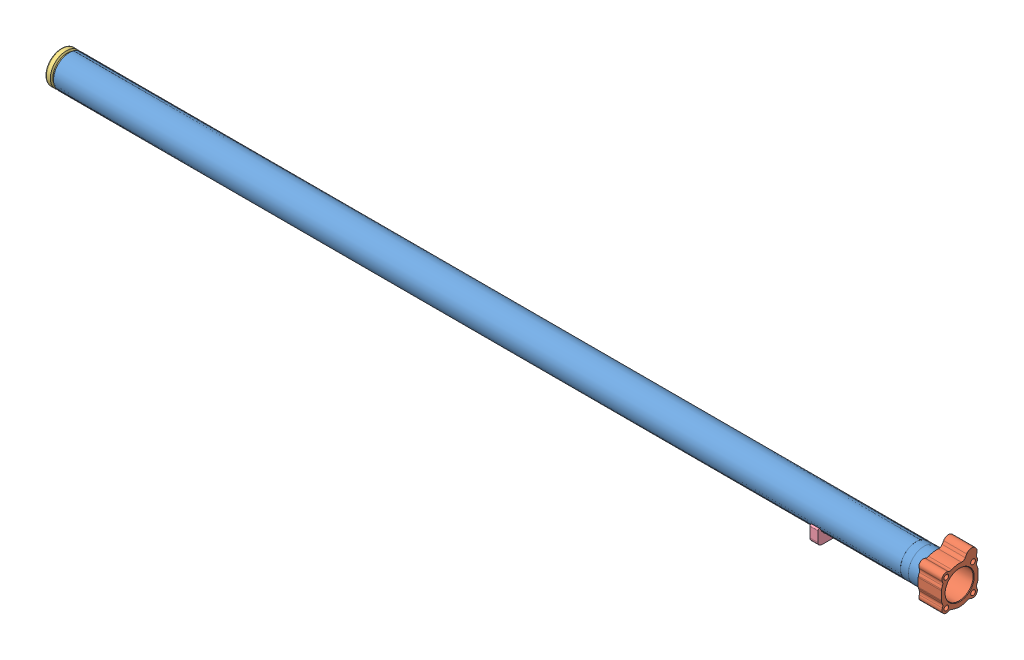
SolidWorks assembly 6344585, configuration Default. Lengths in mm.
Overall size (2270 118.03 92).
4 component instances, 4 part files, 12 mates.
Components (placement in the parent):
- 6344586-1: 6344586 [Default] at (-2237 0 0) x (-1 0 0) z (0 0 -1) size (2181 80 80)
- 6344547-1: 6344547 [Default] at (1 0 0) x (0 0 1) z (-1 0 0) size (92 113.03 58)
- 6344587-1: 6344587 [Default] at (-2235 0 0) x (-1 0 0) z (0 0 -1) size (35 80 80)
- 6304256-1: 6304256 [Default] at (-323 0 0) x (0 0 -1) z (1 0 0) size (86 38.4 20)
Mates (geometry in assembly coordinates):
- Coincident11: coincident aligned: plane of 6344547-1 through (0 90 0) normal (1 0 0); plane of assembly through (0 0 0) normal (1 0 0)
- Concentric4: concentric aligned: cylinder of 6344586-1 through (-2114.2158 0 0) axis (1 0 0) radius 40; cylinder of 6344547-1 through (-59 0 0) axis (1 0 0) radius 47.5
- Concentric5: concentric: cylinder of 6344547-1 through (-59 0 0) axis (1 0 0) radius 47.5
- Coincident12: coincident anti-aligned: plane of 6344586-1 through (-56 37.5 0) normal (1 0 0); plane of 6344547-1 through (-56 37.5 0) normal (-1 0 0)
- Parallel6: parallel aligned: plane of 6344547-1 through (1 0 0) normal (0 0 1); plane of assembly through (0 0 0) normal (0 0 1)
- Parallel7: parallel anti-aligned: plane of 6344586-1 through (-2237 0 0) normal (0 0 -1); plane of assembly through (0 0 0) normal (0 0 1)
- Concentric6: concentric aligned: cylinder of 6344586-1 through (-2114.2158 0 0) axis (1 0 0) radius 35; cylinder of 6344587-1 through (-2203.7231 0 0) axis (1 0 0) radius 36
- Coincident16: coincident anti-aligned: plane of 6344586-1 through (-2237 35 0) normal (-1 0 0); plane of 6344587-1 through (-2237 36 0) normal (1 0 0)
- Coincident17: coincident anti-aligned: plane of 6344587-1 through (-2235 0 0) normal (0 0 -1); plane of assembly through (0 0 0) normal (0 0 1)
- Concentric7: concentric anti-aligned: cylinder of 6344586-1 through (-2114.2158 0 0) axis (1 0 0) radius 40; cylinder of 6304256-1 through (-313 0 0) axis (-1 0 0) radius 40.5
- Distance4: distance = 265 mm anti-aligned: plane of 6344547-1 through (-58 37.5 0) normal (-1 0 0); plane of 6304256-1 through (-323 0 0) normal (1 0 0)
- Parallel8: parallel aligned: plane of 6304256-1 through (-323 0 0) normal (0 1 0); plane of assembly through (0 0 0) normal (0 1 0)
